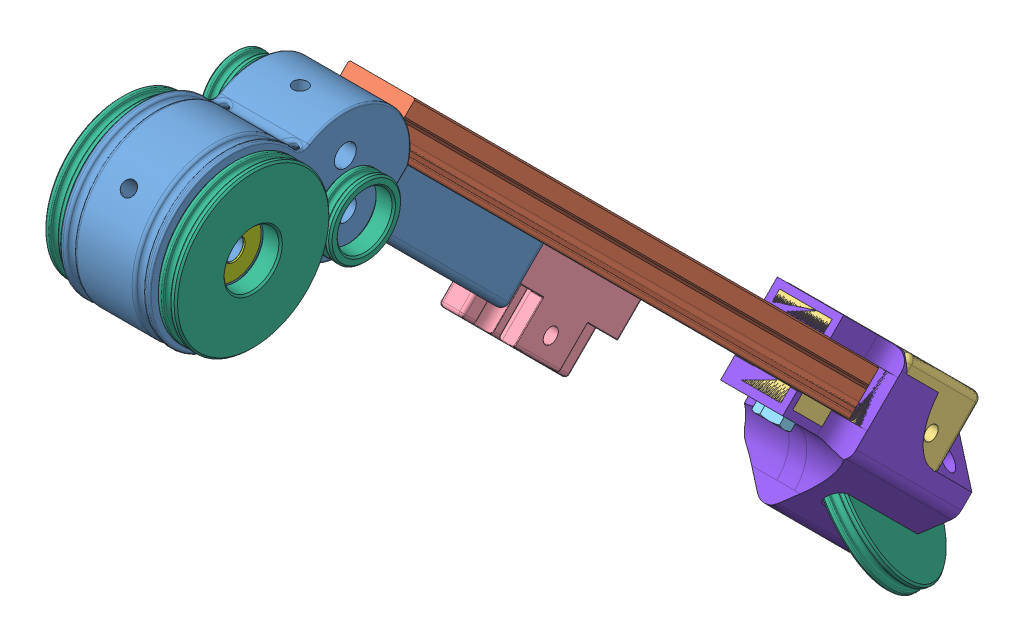
SolidWorks assembly Assem1, configuration Default. Lengths in mm.
Overall size (19.85 112.67 128.62).
16 component instances, 8 part files, 31 mates.
Components (placement in the parent):
- joint3-1: joint3 [Default] at origin size (13.67 41.16 59.05)
- needle_driveactive_base-1: needle_driveactive_base [Default] at (-114.2812 -12.8355 76.3184) x (1 0 0) z (0 0.707107 0.707107) size (9.6 6.3 100)
  - rail_TS_04_09_50_1.SLDPTactive-1: rail_TS_04_09_50_1.SLDPTactive [Default] at (114.2812 79.3988 -72.1414) x (1 0 0) z (0 1 0) size (9.6 100 6.3)
  - end_stopactive-1: end_stopactive [Default] at (114.2852 82.675 -157.1414) x (-1 0 0) z (0 -1 0) size (15.1 25.11 12.45) (hidden)
  - cable_clampactive-1: cable_clampactive [Default] at (109.0312 68.5988 -107.174) x (0 0 -1) z (1 0 0) size (22.06 11.5 6.5) (hidden)
- 90690A030_BRASS HEX NUT-1: 90690A030_BRASS HEX NUT [90690A030] at (0 -66.6764 -85.0011) x (1 0 0) z (0 0.707107 -0.707107) size (4 4.62 1.83)
- 90690A030_BRASS HEX NUT-2: 90690A030_BRASS HEX NUT [90690A030] at (-0.0476 -25.3363 -41.6811) x (0.186782 -0.694663 -0.694663) z (0 0.707107 -0.707107) size (4 4.62 1.83)
- 90690A030_BRASS HEX NUT-3: 90690A030_BRASS HEX NUT [90690A030] at (0.1893 -10.9824 -27.3271) x (-0.944176 0.232951 0.232951) z (0 -0.707107 0.707107) size (4 4.62 1.83)
- Pulley_configurable-2: Pulley_configurable [p3_bearing] at (-8.1431 3.4321 -16.3775) x (0 0.144605 0.989489) z (0 -0.989489 0.144605) size (10.4 2.78 10.4)
- Pulley_configurable-3: Pulley_configurable [p3_bearing] at (8.1431 -3.3562 -16.3775) x (0 0.144605 0.989489) z (0 -0.989489 0.144605) size (10.4 2.78 10.4)
- Pulley_configurable-4: Pulley_configurable [p1_bearing] at (-8.1431 0 0) x (0 0.438836 0.898567) z (0 -0.898567 0.438836) size (22.4 2.78 22.4)
- Pulley_configurable-5: Pulley_configurable [p1_bearing] at (8.1431 0 0) x (0 -0.409575 0.912276) z (0 -0.912276 -0.409575) size (22.4 2.78 22.4)
- 10thouspacer_3125shaft-1: 10thouspacer_3125shaft [Default] at (6.754 0 0) x (0 0 1) z (-1 0 0) size (7.87 7.87 0.25)
- 10thouspacer_3125shaft-2: 10thouspacer_3125shaft [Default] at (-6.5 0 0) x (0 0.189881 0.981807) z (-1 0 0) size (7.87 7.87 0.25)
- end_stopactive2_tilt-1: end_stopactive2_tilt [Default] at (0.004 -65.5265 -93.2221) x (-1 0 0) z (0 -0.707107 0.707107) size (15.25 31.5 20.72)
- Pulley_configurable-6: Pulley_configurable [p1_bearing] at (-0.004 -83.5409 -99.9564) x (0.06583 0.662003 0.746605) z (0.73713 -0.536568 0.410772) size (22.4 2.78 22.4)
Mates (geometry in assembly coordinates):
- Coincident45: coincident: plane of joint3-1 through (6.5 11.5665 -11.5665) normal (0 0.707107 -0.707107); plane of needle_driveactive_base-1/rail_TS_04_09_50_1.SLDPTactive-1 through (-3 9.974 -13.159) normal (0 -0.707107 0.707107)
- Concentric47: concentric: cylinder of joint3-1 through (0 -40.0588 1.5184) axis (0 0.707107 -0.707107) radius 1.25; cylinder of needle_driveactive_base-1/rail_TS_04_09_50_1.SLDPTactive-1 through (0 -6.0137 -32.5267) axis (0 0.707107 -0.707107) radius 1.2
- Parallel2: parallel: plane of joint3-1 through (-5 -30.9914 -39.9822) normal (-1 0 0); plane of needle_driveactive_base-1/rail_TS_04_09_50_1.SLDPTactive-1 through (-4.8 13.5802 -16.7653) normal (-1 0 0)
- Coincident53: coincident: plane of joint3-1 through (1.6022 -11.8463 -29.3224) normal (-0.944176 0.232951 0.232951); plane of 90690A030_BRASS HEX NUT-3 through (1.6973 -12.7849 -27.9983) normal (0.944176 -0.232951 -0.232951)
- Coincident54: coincident: plane of joint3-1 through (0 8.7381 -8.7381) normal (0 -0.707107 0.707107); plane of 90690A030_BRASS HEX NUT-3 through (1.6973 -11.6535 -29.1296) normal (0 0.707107 -0.707107)
- Coincident55: coincident: plane of joint3-1 through (0.8084 -8.8939 -26.3701) normal (0.186782 -0.694663 -0.694663); plane of 90690A030_BRASS HEX NUT-3 through (0.9502 -10.0062 -25.2196) normal (-0.186782 0.694663 0.694663)
- Coincident56: coincident: plane of joint3-1 through (-2.4106 -24.9983 -42.4745) normal (0.757394 0.461711 0.461711); plane of 90690A030_BRASS HEX NUT-2 through (-0.8084 -26.3125 -43.7886) normal (-0.757394 -0.461711 -0.461711)
- Coincident57: coincident: plane of joint3-1 through (-0.8084 -26.3125 -43.7886) normal (-0.186782 0.694663 0.694663); plane of 90690A030_BRASS HEX NUT-2 through (1.4604 -26.0074 -43.4836) normal (0.186782 -0.694663 -0.694663)
- Coincident58: coincident: plane of joint3-1 through (0 8.7381 -8.7381) normal (0 -0.707107 0.707107); plane of 90690A030_BRASS HEX NUT-2 through (-1.5555 -23.5338 -41.0099) normal (0 0.707107 -0.707107)
- Concentric41: concentric: circle of needle_driveactive_base-1/end_stopactive-1; circle of 90690A030_BRASS HEX NUT-1
- Coincident44: coincident: plane of needle_driveactive_base-1/end_stopactive-1 through (0 -66.1107 -85.5667) normal (0 -0.707107 0.707107); plane of 90690A030_BRASS HEX NUT-1 through (-2 -66.9272 -86.3832) normal (0 0.707107 -0.707107)
- Concentric65: concentric: cylinder of joint3-1 through (6.5 0 0) axis (-1 0 0) radius 1.5875; cylinder of Pulley_configurable-4 through (-8.1431 0 0) axis (1 0 0) radius 3.9688
- Concentric73: concentric: cylinder of joint3-1 through (6.5 0 0) axis (-1 0 0) radius 1.5875; cylinder of Pulley_configurable-5 through (8.1431 0 0) axis (1 0 0) radius 3.9688
- Coincident82: coincident: plane of joint3-1 through (0 0 0) normal (0 0 1); plane of assembly through (0 0 0) normal (0 0 1)
- Coincident83: coincident: plane of joint3-1 through (0 0 0) normal (0 1 0); plane of assembly through (0 0 0) normal (0 1 0)
- Coincident84: coincident: plane of joint3-1 through (0 0 0) normal (1 0 0); plane of assembly through (0 0 0) normal (1 0 0)
- Coincident85: coincident: plane of Pulley_configurable-3 through (9.5321 -3.3562 -16.3775) normal (1 0 0); plane of Pulley_configurable-5 through (9.5321 0 0) normal (1 0 0)
- Coincident86: coincident: plane of Pulley_configurable-2 through (-9.5321 3.4321 -16.3775) normal (-1 0 0); plane of Pulley_configurable-4 through (-9.5321 0 0) normal (-1 0 0)
- Concentric74: concentric: cylinder of joint3-1 through (6.5 0 0) axis (-1 0 0) radius 1.5875; cylinder of 10thouspacer_3125shaft-1 through (6.5 0 0) axis (1 0 0) radius 1.6002
- Coincident87: coincident: plane of joint3-1 through (6.5 0 0) normal (1 0 0); plane of 10thouspacer_3125shaft-1 through (6.5 0 0) normal (-1 0 0)
- Coincident88: coincident: plane of Pulley_configurable-5 through (6.754 0 0) normal (-1 0 0); plane of 10thouspacer_3125shaft-1 through (6.754 0 0) normal (1 0 0)
- Concentric75: concentric: cylinder of joint3-1 through (6.5 0 0) axis (-1 0 0) radius 1.5875; cylinder of 10thouspacer_3125shaft-2 through (-6.754 0 0) axis (1 0 0) radius 1.6002
- Coincident89: coincident: plane of Pulley_configurable-4 through (-6.754 0 0) normal (1 0 0); plane of 10thouspacer_3125shaft-2 through (-6.754 0 0) normal (-1 0 0)
- Coincident90: coincident: plane of joint3-1 through (-6.5 0 0) normal (-1 0 0); plane of 10thouspacer_3125shaft-2 through (-6.5 0 0) normal (1 0 0)
- Concentric76: concentric: cylinder of joint3-1 through (6.5 -3.3562 -16.3775) axis (-1 0 0) radius 1.5875; cylinder of Pulley_configurable-3 through (8.1431 -3.3562 -16.3775) axis (1 0 0) radius 3.9688
- Concentric77: concentric: cylinder of joint3-1 through (6.5 3.4321 -16.3775) axis (-1 0 0) radius 1.5875; cylinder of Pulley_configurable-2 through (-8.1431 3.4321 -16.3775) axis (1 0 0) radius 3.9688
- Coincident91: coincident: plane of needle_driveactive_base-1/rail_TS_04_09_50_1.SLDPTactive-1 through (-2.3 14.4287 -17.6138) normal (0 0.707107 -0.707107); plane of end_stopactive2_tilt-1 through (4.6167 -67.9492 -99.9917) normal (0 -0.707107 0.707107)
- Concentric78: concentric: cylinder of end_stopactive2_tilt-1 through (10.2546 -75.5587 -107.9386) axis (-0.672537 -0.523304 0.523304) radius 1.524; cylinder of Pulley_configurable-6 through (-0.004 -83.5409 -99.9564) axis (0.672537 0.523304 -0.523304) radius 3.9688
- Width2: width: plane of end_stopactive2_tilt-1 through (-7.1382 -77.5234 -105.9739) normal (-0.672537 -0.523304 0.523304); plane of end_stopactive2_tilt-1 through (-9.1558 -79.0933 -104.404) normal (0.672537 0.523304 -0.523304); plane of Pulley_configurable-6 through (0.9302 -82.814 -100.6833) normal (0.672537 0.523304 -0.523304); plane of Pulley_configurable-6 through (-0.9382 -84.2678 -99.2295) normal (-0.672537 -0.523304 0.523304)
- Concentric80: concentric: cylinder of needle_driveactive_base-1/rail_TS_04_09_50_1.SLDPTactive-1 through (0 -62.5823 -89.0952) axis (0 0.707107 -0.707107) radius 1.2; cylinder of end_stopactive2_tilt-1 through (0 -64.3076 -87.3699) axis (0 0.707107 -0.707107) radius 1.3526
- Parallel3: parallel: plane of needle_driveactive_base-1/rail_TS_04_09_50_1.SLDPTactive-1 through (-4.8 13.5802 -16.7653) normal (-1 0 0); plane of end_stopactive2_tilt-1 through (-4.504 -58.4554 -86.151) normal (-1 0 0)
